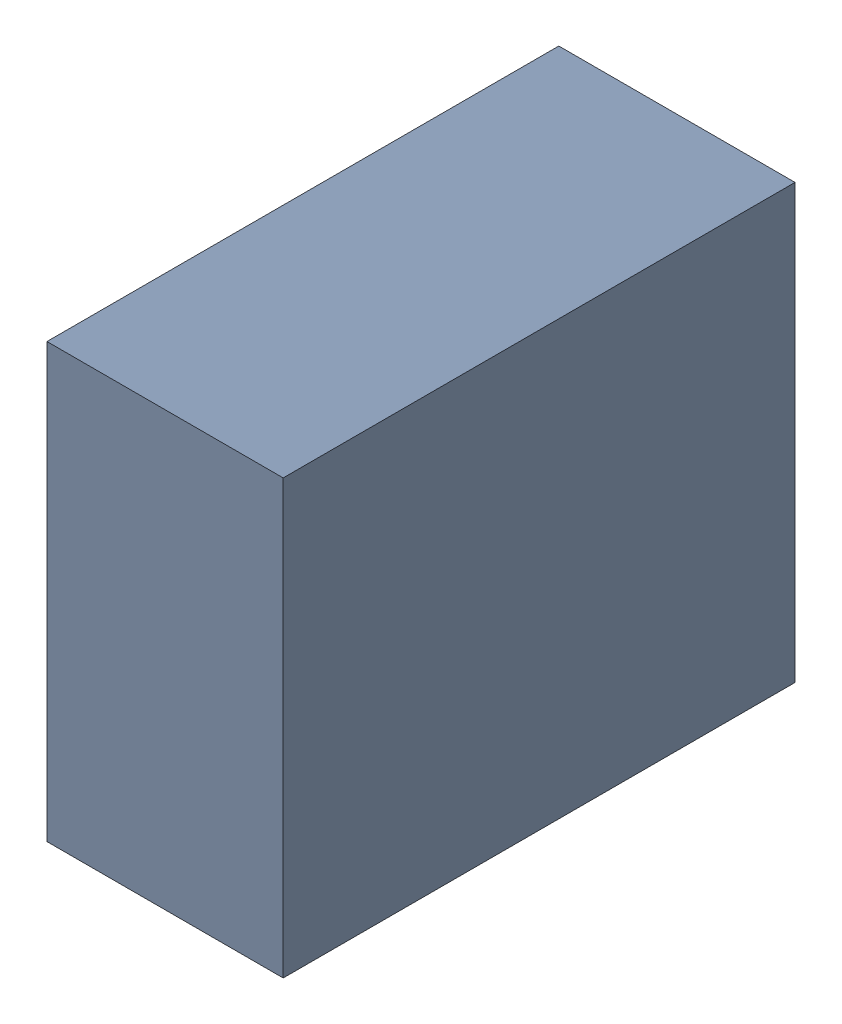
SolidWorks assembly C23_TDA1, configuration Standard. Lengths in mm.
Overall size (0.6 1.1 1.3).
2 component instances, 1 part files, 0 mates.
Components (placement in the parent):
- 885542376-1: 885542376 [Standard] at (4.27 51.14 0) size (0.6 1.1 1.3)
  - Extruded_25-1: Extruded_25 [Standard] at origin size (0.6 1.1 1.3)
